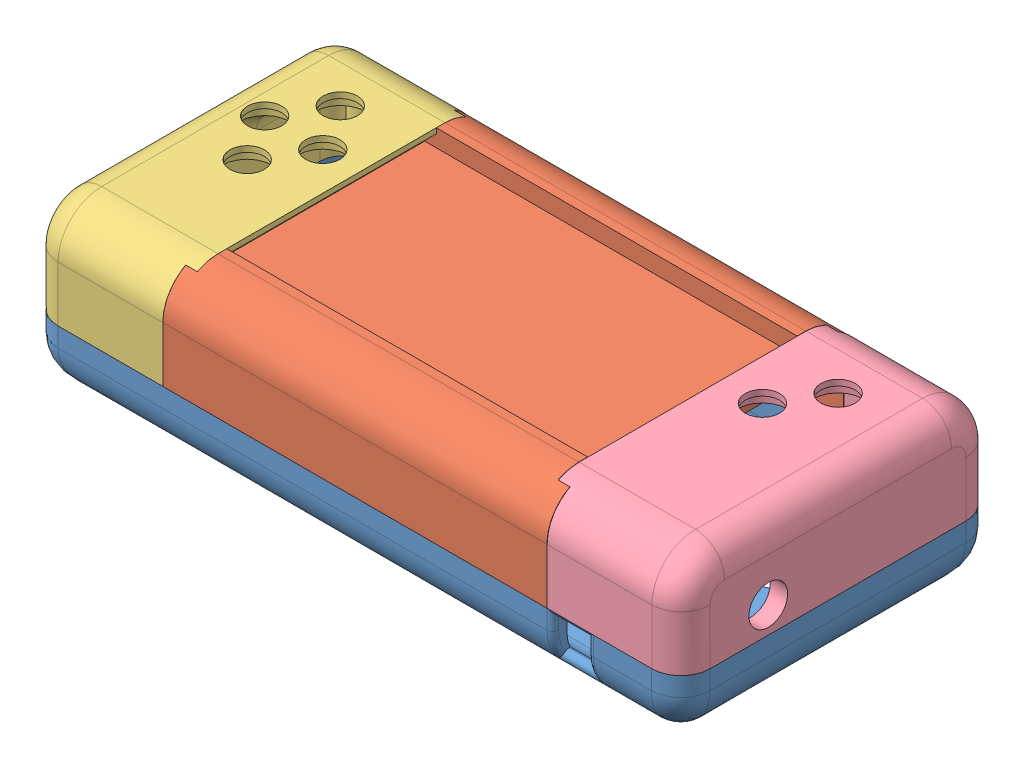
SolidWorks assembly doodleboy_asssem, configuration Default. Lengths in mm.
Overall size (284.61 70.71 137.16).
4 component instances, 4 part files, 10 mates.
Components (placement in the parent):
- back_panel-1: back_panel [Default] at origin size (284.48 27.53 137.16)
- front_panel-1: front_panel [Default] at (58.42 57.875 0) size (167.64 43.16 137.16)
- right_panel-1: right_panel [Default] at (0 62.9702 0) size (63.5 43.18 137.16)
- left_panel-1: left_panel [Default] at (284.607 62.9702 -137.16) x (-1 0 0) z (0 0 -1) size (63.5 43.18 137.16)
Mates (geometry in assembly coordinates):
- Coincident1: coincident anti-aligned: plane of back_panel-1 through (0 27.4102 0) normal (0 1 0); plane of front_panel-1 through (58.42 27.4102 0) normal (0 -1 0)
- Coincident2: coincident anti-aligned: plane of back_panel-1 through (0 27.4102 0) normal (0 1 0); plane of front_panel-1 through (58.42 27.4102 0) normal (0 -1 0)
- Coincident3: coincident aligned: plane of back_panel-1 through (0 5.08 -137.16) normal (0 0 -1); plane of front_panel-1 through (58.42 70.575 -137.16) normal (0 0 -1)
- Concentric1: concentric anti-aligned: circle of back_panel-1; circle of front_panel-1
- Coincident4: coincident anti-aligned: plane of back_panel-1 through (0 27.4102 0) normal (0 1 0); plane of right_panel-1 through (0 27.4102 0) normal (0 -1 0)
- Concentric2: concentric anti-aligned: circle of back_panel-1; circle of right_panel-1
- Concentric3: concentric anti-aligned: circle of back_panel-1; circle of right_panel-1
- Coincident5: coincident anti-aligned: plane of back_panel-1 through (0 27.4102 0) normal (0 1 0); plane of left_panel-1 through (284.607 27.4102 -137.16) normal (0 -1 0)
- Concentric4: concentric anti-aligned: circle of back_panel-1; circle of left_panel-1
- Concentric5: concentric anti-aligned: circle of back_panel-1; circle of left_panel-1
